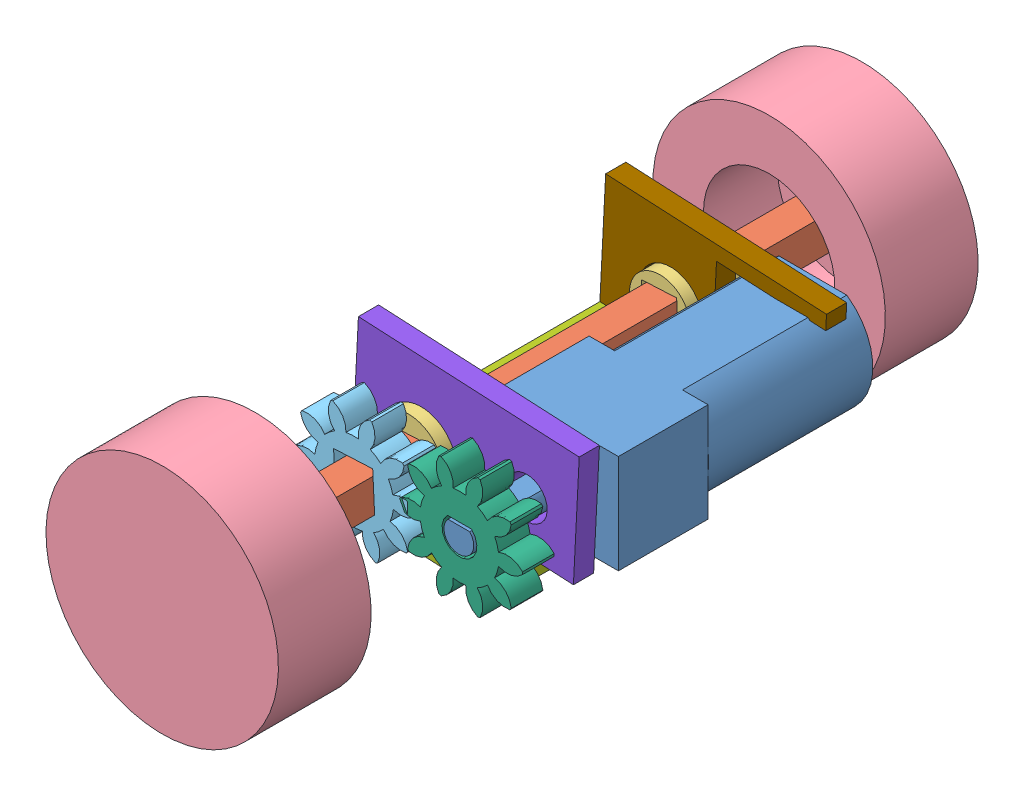
SolidWorks assembly Motor Assembly, configuration Default. Lengths in mm.
Overall size (32.24 31.27 70.33).
11 component instances, 9 part files, 39 mates.
Components (placement in the parent):
- Motor-1: Motor [Default] at (4.6695 47.3908 23.3768) x (0 0 1) z (-1 0 0) size (35.59 9.96 12.06)
- Axle-1: Axle [Default] at (-5.5885 46.5792 17.8283) x (0 0 -1) z (0.998799 0.048988 0) size (63.12 3.3 3.3)
- Bushing-1: Bushing [Default] at (-5.7215 46.6998 23.0333) x (0 0 1) z (0.048988 -0.998799 0) size (5.08 7.11 7.11)
- Tire-1: Tire [Default] at (-5.5885 46.5792 52.9946) x (0 0 -1) z (0.440317 -0.897843 0) size (9.32 23.37 23.37)
- Bushing-2: Bushing [Default] at (-5.7215 46.6998 2.8388) x (0 0 -1) z (0.048988 -0.998799 0) size (5.08 7.11 7.11)
- Tire-2: Tire [Default] at (-5.5885 46.5792 -17.338) x (0 0 1) z (0.16618 -0.986095 0) size (9.32 23.37 23.37)
- Gear2A-1: Gear2A [Inch - Spur gear 24DP 10T 20PA .125FW ---S10N3.0H2.0L0.0787N] at (-5.9211 46.8808 33.3717) x (0 0 -1) z (0.998799 0.048988 0) size (3.17 12.15 12.7)
- Gear2M-1: Gear2M [Inch - Spur gear 24DP 10T 20PA .125FW ---S10N3.0H2.0L0.0787N] at (4.6695 47.3908 33.3717) x (0 0 -1) z (1 0 0) size (3.17 12.15 12.7)
- Motor Base-1: Motor Base [Default] at (-3.9533 40.811 13.1607) x (0 0 -1) z (0.998703 -0.050923 0) size (34 3.56 18)
- Motor Left-1: Motor Left [Default] at (-3.9533 40.811 13.4147) x (0 0 -1) z (0.998703 -0.050923 0) size (2.03 13.46 22.23)
- Motor Right-1: Motor Right [Default] at (-3.9533 40.811 12.9067) x (0 0 -1) z (0.998703 -0.050923 0) size (2.03 13.46 22.23)
Mates (geometry in assembly coordinates):
- Parallel1: parallel aligned: plane of Motor-1 through (4.6695 47.3908 23.3768) normal (0 0 1); plane of Axle-1 through (-5.5885 46.5792 49.3878) normal (0 0 1)
- Coincident1: coincident anti-aligned: plane of Axle-1 through (-3.8586 45.0111 -13.7312) normal (0.048988 -0.998799 0); plane of Bushing-1 through (-7.4103 44.8369 28.1133) normal (-0.048988 0.998799 0)
- Coincident2: coincident anti-aligned: plane of Axle-1 through (-4.0203 48.3091 -13.7312) normal (0.998799 0.048988 0); plane of Bushing-1 through (-3.8586 45.0111 28.1133) normal (-0.998799 -0.048988 0)
- Coincident3: coincident anti-aligned: plane of Axle-1; plane of ? through (2.7999 20.6303 40.2247) normal (-1 0 0)
- Coincident4: coincident anti-aligned: plane of Axle-1; plane of ? through (-0.2001 20.6303 40.2247) normal (0 -1 0)
- Parallel2: parallel aligned: plane of Motor-1 through (15.2924 19.1303 33.6084) normal (0 0 1); plane of ? through (15.2924 19.1303 40.1217) normal (0 0 1)
- Coincident5: coincident anti-aligned: plane of Motor-1 through (14.1908 20.1463 43.6668) normal (0 1 0); plane of ? through (16.394 20.1463 40.1217) normal (0 -1 0)
- Concentric1: concentric aligned: cylinder of Motor-1 through (15.2924 19.1303 43.6668) axis (0 0 -1) radius 1.4986; cylinder of ? through (15.2924 19.1303 40.1217) axis (0 0 -1) radius 1.4986
- Concentric2: concentric aligned: cylinder of Axle-1 through (-5.5885 46.5792 46.2128) axis (0 0 1) radius 1.27; cylinder of Tire-1 through (-5.5885 46.5792 46.2128) axis (0 0 1) radius 1
- Coincident7: coincident anti-aligned: plane of Axle-1 through (-5.5885 46.5792 46.2128) normal (0 0 1); plane of Tire-1 through (-5.5885 46.5792 46.2128) normal (0 0 -1)
- Coincident8: coincident anti-aligned: plane of Axle-1; plane of ? through (2.0059 17.6303 47.7503) normal (0 1 0)
- Coincident9: coincident anti-aligned: plane of Axle-1; plane of ? through (-0.9941 20.6303 47.7503) normal (1 0 0)
- Coincident11: coincident anti-aligned: plane of Axle-1 through (-5.5885 46.5792 -10.5562) normal (0 0 -1); plane of Tire-2 through (-5.5885 46.5792 -10.5562) normal (0 0 1)
- Concentric4: concentric aligned: cylinder of Axle-1 through (-5.5885 46.5792 -10.5562) axis (0 0 -1) radius 1.27; cylinder of Tire-2 through (-5.5885 46.5792 -10.5562) axis (0 0 -1) radius 1
- Coincident12: coincident anti-aligned: plane of Axle-1 through (-3.8586 45.0111 -13.7312) normal (0.048988 -0.998799 0); plane of Bushing-2 through (-3.8586 45.0111 -2.2412) normal (-0.048988 0.998799 0)
- Coincident13: coincident anti-aligned: plane of Axle-1 through (-4.0203 48.3091 -13.7312) normal (0.998799 0.048988 0); plane of Bushing-2 through (-3.8586 45.0111 -2.2412) normal (-0.998799 -0.048988 0)
- Coincident14: coincident aligned: plane of ? through (0.5059 19.1303 47.7503) normal (0 0 1); plane of ? through (15.2924 19.1303 47.7503) normal (0 0 1)
- Coincident17: coincident aligned: plane of ? through (20.6939 34.7295 43.1979) normal (0 0 1); plane of ? through (11.2882 39.1999 43.1979) normal (0 0 1)
- Coincident18: coincident aligned: plane of ? through (15.2924 19.1303 41.5653) normal (0 0 1); plane of ? through (28.1951 18.74 41.5653) normal (0 0 1)
- Coincident19: coincident anti-aligned: plane of Motor-1 through (12.3161 48.1661 23.3768) normal (0 0 1); plane of ? through (-4.9605 54.6177 23.3768) normal (0 0 -1)
- Concentric5: concentric anti-aligned: cylinder of Motor-1 through (12.3161 48.1661 24.1388) axis (0 0 -1) radius 1.9939; cylinder of ? through (12.3161 48.1661 -4.7812) axis (0 0 1) radius 2.0574
- Concentric6: concentric anti-aligned: cylinder of Bushing-1 through (1.9737 46.9469 25.4088) axis (0 0 -1) radius 3.048; cylinder of ? through (1.9737 46.9469 -4.7812) axis (0 0 1) radius 3.175
- Concentric7: concentric aligned: cylinder of Bushing-2 through (1.9737 46.9469 -0.9712) axis (0 0 1) radius 3.048; cylinder of ? through (1.9737 46.9469 -4.7812) axis (0 0 1) radius 3.175
- Coincident20: coincident anti-aligned: plane of Bushing-2 through (1.9737 46.9469 -0.9712) normal (0 0 1); plane of ? through (-4.9605 54.6177 -0.9712) normal (0 0 -1)
- Coincident21: coincident anti-aligned: plane of Bushing-1 through (1.9737 46.9469 25.4088) normal (0 0 -1); plane of ? through (-4.9605 54.6177 25.4088) normal (0 0 1)
- Coincident22: coincident anti-aligned: plane of Motor-1 through (6.3344 43.1877 14.3598) normal (0 -1 0); plane of ? through (4.0395 43.1877 12.2188) normal (0 1 0)
- Coincident26: coincident aligned: plane of ? through (1.4224 47.8719 33.4044) normal (0 0 1); plane of ? through (10.7282 43.3966 33.4044) normal (0 0 1)
- Coincident27: coincident anti-aligned: plane of Axle-1 through (-3.8586 45.0111 -13.7312) normal (0.048988 -0.998799 0); plane of Gear2A-1 through (-3.8586 45.0111 33.3717) normal (-0.048988 0.998799 0)
- Coincident28: coincident anti-aligned: plane of Axle-1 through (-4.0203 48.3091 -13.7312) normal (0.998799 0.048988 0); plane of Gear2A-1 through (-4.0514 48.9433 33.3717) normal (-0.998799 -0.048988 0)
- Concentric8: concentric aligned: cylinder of Motor-1 through (4.6695 47.3908 33.4352) axis (0 0 -1) radius 1.4986; cylinder of Gear2M-1 through (4.6695 47.3908 33.3717) axis (0 0 -1) radius 1.7526
- Coincident29: coincident aligned: plane of Gear2A-1 through (-5.9211 46.8808 33.3717) normal (0 0 1); plane of Gear2M-1 through (4.6695 47.3908 33.3717) normal (0 0 1)
- Coincident30: coincident anti-aligned: plane of Motor Base-1 through (-3.8498 42.8403 13.1607) normal (0.050923 0.998703 0); plane of Motor Left-1 through (-3.8498 42.8403 13.4147) normal (-0.050923 -0.998703 0)
- Coincident31: coincident anti-aligned: plane of Motor Base-1 through (-3.8498 42.8403 13.1607) normal (0.050923 0.998703 0); plane of Motor Right-1 through (-12.8382 43.2986 -4.0933) normal (-0.050923 -0.998703 0)
- Coincident32: coincident aligned: plane of Motor Base-1 through (-12.8382 43.2986 30.1607) normal (-0.998703 0.050923 0); plane of Motor Left-1 through (-12.8382 43.2986 30.4147) normal (-0.998703 0.050923 0)
- Coincident33: coincident aligned: plane of Motor Base-1 through (-12.8382 43.2986 30.1607) normal (-0.998703 0.050923 0); plane of Motor Right-1 through (-12.8382 43.2986 29.9067) normal (-0.998703 0.050923 0)
- Coincident34: coincident anti-aligned: plane of Motor Base-1 through (-9.6708 39.5765 -0.2833) normal (0 0 1); plane of Motor Right-1 through (-12.2561 54.7138 -0.2833) normal (0 0 -1)
- Coincident35: coincident anti-aligned: plane of Motor Base-1 through (-9.6708 39.5765 26.6047) normal (0 0 -1); plane of Motor Left-1 through (-12.2561 54.7138 26.6047) normal (0 0 1)
- Concentric9: concentric anti-aligned: cylinder of Bushing-1 through (-5.7215 46.6998 26.8433) axis (0 0 -1) radius 3.048; cylinder of Motor Left-1 through (-5.7215 46.6998 -3.5853) axis (0 0 1) radius 3.175
- Concentric10: concentric anti-aligned: cylinder of Motor-1 through (4.6695 47.3908 24.1388) axis (0 0 -1) radius 1.9939; cylinder of Motor Left-1 through (4.6695 47.3908 -3.5853) axis (0 0 1) radius 2.0574
